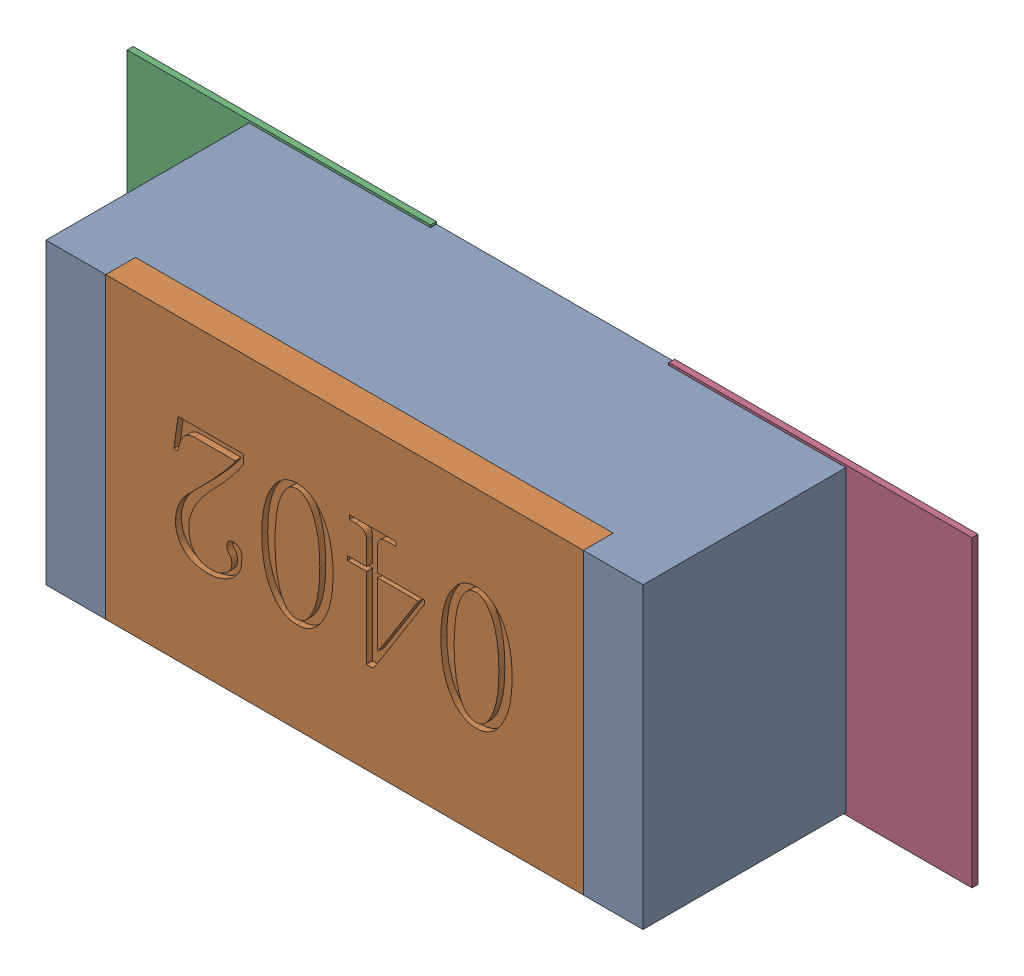
SolidWorks assembly R27, configuration Défaut. Lengths in mm.
Overall size (1.42 0.51 0.35).
5 component instances, 2 part files, 0 mates.
Components (placement in the parent):
- R0402-1: R0402 [Défaut] at (20.0335 -27.3091 0) x (-1 0 0) z (0 0 1) size (1 0.5 0.35)
- 6504207776-1: 6504207776 [Défaut] at (19.5835 -27.3092 0) size (0.51 0.51 0.01)
  - Extruded-1: Extruded [Défaut] at origin size (0.51 0.51 0.01)
- 6504207776-2: 6504207776 [Défaut] at (20.4906 -27.3092 0) size (0.51 0.51 0.01)
  - Extruded-1: Extruded [Défaut] at origin size (0.51 0.51 0.01)
